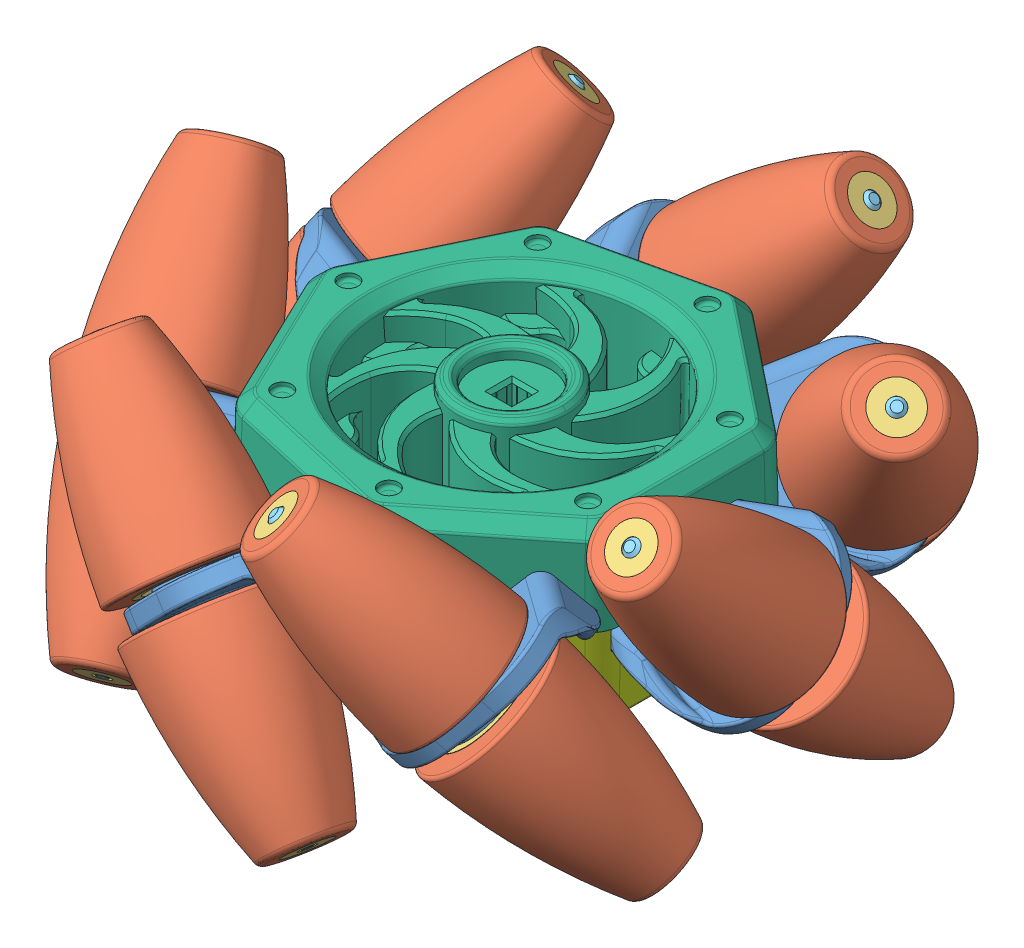
SolidWorks assembly Mecanum Right, configuration Default. Lengths in mm.
Overall size (110.3 64.91 110.26).
58 component instances, 7 part files, 0 mates.
Components (placement in the parent):
- Bracket Right-1: Bracket Right [Default] at (0 200 0) x (0.623334 0 -0.781956) z (-0.781956 0 -0.623334) size (28.34 25.51 28.03)
- Roller-2: Roller [Default] at (-36.4141 199.7525 -17.2503) x (0 -0.669407 -0.742896) z (0.951825 -0.227804 0.205269) size (22.31 28.6 22.31)
- Roller Hub-1: Roller Hub [Default] at (24.9941 200.1768 31.6042) x (0.175196 0.615989 -0.768026) z (-0.81476 -0.347214 -0.464337) size (15.2 28.65 15.2)
- Washer-3: Washer [Default] at (-15.7476 193.0527 -37.733) x (-0.491142 0.615989 0.615904) z (0.689343 0.707107 -0.157501) size (6 6 6.25)
- Washer-4: Washer [Default] at (-15.7278 206.9473 37.7412) x (0.709708 0.615989 -0.341865) z (-0.689425 0.707107 -0.15714) size (6 6 6.25)
- Roller-4: Roller [Default] at (40.2927 200.1768 0.1627) x (0 -0.707107 0.707107) z (1 -0.000175 -0.000175) size (22.31 28.6 22.31)
- Bracket Right-2: Bracket Right [Default] at (0 200 0) x (1 0 -0.000175) z (-0.000175 0 -1) size (28.34 25.51 28.03)
- Roller Hub-3: Roller Hub [Default] at (-36.2301 200.1768 -17.6326) x (0.17533 0.615989 0.767995) z (0.935537 -0.347214 0.064912) size (15.2 28.65 15.2)
- Roller Hub-4: Roller Hub [Default] at (25.3257 199.7525 31.3396) x (-0.175196 -0.615989 0.768026) z (-0.81476 -0.347214 -0.464337) size (15.2 28.65 15.2)
- Washer-7: Washer [Default] at (-2.202 206.9473 -40.8279) x (-0.491142 0.615989 0.615904) z (0.689343 0.707107 -0.157501) size (6 6 6.25)
- Roller-7: Roller [Default] at (-36.3744 200.1768 17.333) x (0 0.669314 0.74298) z (0.951717 0.228078 -0.205464) size (22.31 28.6 22.31)
- Roller-8: Roller [Default] at (40.2926 199.7525 -0.2616) x (0 0.707107 -0.707107) z (1 -0.000175 -0.000175) size (22.31 28.6 22.31)
- Bracket Right-3: Bracket Right [Default] at (0 200 0) x (0.623607 0 0.781738) z (0.781738 0 -0.623607) size (28.34 25.51 28.03)
- Roller Hub-5: Roller Hub [Default] at (-36.4141 199.7525 -17.2503) x (-0.17533 -0.615989 -0.767995) z (0.935537 -0.347214 0.064912) size (15.2 28.65 15.2)
- Washer-9: Washer [Default] at (30.5625 193.0527 27.1606) x (0.175196 0.615989 -0.768026) z (-0.552695 0.707107 0.441053) size (6 6 6.25)
- Pin-3: Pin [Default] at (25.0549 200.1061 31.5557) x (0.552772 0.707107 -0.440957) z (0.623743 -0.000175 0.781629) size (2.6 61.8 2.6)
- Roller-11: Roller [Default] at (25.254 200.1768 -31.3969) x (-0.787755 0.615989 0) z (-0.271506 -0.347214 0.897623) size (22.31 28.6 22.31)
- Roller-12: Roller [Default] at (-36.1902 199.7525 17.7152) x (0 -0.669314 -0.74298) z (0.951717 0.228078 -0.205464) size (22.31 28.6 22.31)
- Roller Hub-7: Roller Hub [Default] at (40.2927 200.1768 0.1627) x (-0.491249 0.615989 -0.615818) z (-0.871019 -0.347214 0.347518) size (15.2 28.65 15.2)
- Bracket Right-4: Bracket Right [Default] at (0 200 0) x (-0.222399 0 0.974956) z (0.974956 0 0.222399) size (28.34 25.51 28.03)
- Washer-12: Washer [Default] at (-39.3196 193.0527 -11.2132) x (0.17533 0.615989 0.767995) z (0.306643 0.707107 -0.637158) size (6 6 6.25)
- Washer-13: Washer [Default] at (19.7021 206.9473 35.8273) x (0.175196 0.615989 -0.768026) z (-0.552695 0.707107 0.441053) size (6 6 6.25)
- Pin-4: Pin [Default] at (-9.0508 200.1061 39.2631) x (0.689398 0.707107 0.15726) z (-0.222229 -0.000175 0.974994) size (2.6 61.8 2.6)
- Roller-15: Roller [Default] at (24.9223 199.7525 -31.6614) x (0.787755 -0.615989 0) z (-0.271506 -0.347214 0.897623) size (22.31 28.6 22.31)
- Roller Hub-9: Roller Hub [Default] at (-36.3744 200.1768 17.333) x (0.709768 0.615989 0.341741) z (0.634031 -0.347214 -0.690976) size (15.2 28.65 15.2)
- Roller Hub-10: Roller Hub [Default] at (40.2926 199.7525 -0.2616) x (0.491249 -0.615989 0.615818) z (-0.871019 -0.347214 0.347518) size (15.2 28.65 15.2)
- Bracket Right-5: Bracket Right [Default] at (0 200 0) x (-0.901001 0 -0.433816) z (-0.433816 0 0.901001) size (28.34 25.51 28.03)
- Washer-16: Washer [Default] at (-33.294 206.9473 -23.7334) x (0.17533 0.615989 0.767995) z (0.306643 0.707107 -0.637158) size (6 6 6.25)
- Roller-16: Roller [Default] at (-9.1266 200.1768 39.2459) x (-0.716002 -0.698098 0) z (-0.109699 0.112512 0.987576) size (22.31 28.6 22.31)
- Pin-6: Pin [Default] at (-36.3407 200.1061 17.4031) x (0.306866 0.707107 0.637051) z (-0.90085 -0.000175 0.434131) size (2.6 61.8 2.6)
- Roller Hub-15: Roller Hub [Default] at (25.254 200.1768 -31.3969) x (-0.787755 0.615989 0) z (-0.271506 -0.347214 0.897623) size (15.2 28.65 15.2)
- Roller Hub-16: Roller Hub [Default] at (-36.1902 199.7525 17.7152) x (-0.709768 -0.615989 -0.341741) z (0.634031 -0.347214 -0.690976) size (15.2 28.65 15.2)
- Washer-18: Washer [Default] at (40.2903 193.0527 -6.9614) x (-0.491249 0.615989 -0.615818) z (0.000247 0.707107 0.707107) size (6 6 6.25)
- Bracket Right-6: Bracket Right [Default] at (0 200 0) x (-0.22257 0 -0.974917) z (-0.974917 0 0.22257) size (28.34 25.51 28.03)
- Roller-18: Roller [Default] at (-8.8024 200.1768 -39.3198) x (-0.716044 0.698055 0) z (0.109944 0.112777 0.987519) size (22.31 28.6 22.31)
- Roller-19: Roller [Default] at (-8.7129 199.7525 39.3401) x (0.716002 0.698098 0) z (-0.109699 0.112512 0.987576) size (22.31 28.6 22.31)
- Pin-8: Pin [Default] at (-36.2639 200.1061 -17.5625) x (-0.306754 0.707107 0.637104) z (-0.901077 -0.000175 -0.433659) size (2.6 61.8 2.6)
- Roller Hub-19: Roller Hub [Default] at (24.9223 199.7525 -31.6614) x (0.787755 -0.615989 0) z (-0.271506 -0.347214 0.897623) size (15.2 28.65 15.2)
- Washer-21: Washer [Default] at (-33.2816 193.0527 23.7508) x (0.709768 0.615989 0.341741) z (-0.306977 0.707107 -0.636997) size (6 6 6.25)
- Washer-22: Washer [Default] at (40.2951 206.9473 6.9333) x (-0.491249 0.615989 -0.615818) z (0.000247 0.707107 0.707107) size (6 6 6.25)
- Bracket Right-7: Bracket Right [Default] at (0 200 0) x (-0.900926 0 0.433974) z (0.433974 0 0.900926) size (28.34 25.51 28.03)
- Roller-21: Roller [Default] at (-9.216 199.7525 -39.2253) x (0.716044 -0.698055 0) z (0.109944 0.112777 0.987519) size (22.31 28.6 22.31)
- Roller Hub-20: Roller Hub [Default] at (-9.1266 200.1768 39.2459) x (0.709708 0.615989 -0.341865) z (-0.144938 -0.347214 -0.926518) size (15.2 28.65 15.2)
- Pin-10: Pin [Default] at (-8.8782 200.1061 -39.3025) x (-0.68937 0.707107 0.15738) z (-0.22274 -0.000175 -0.974878) size (2.6 61.8 2.6)
- Washer-24: Washer [Default] at (19.6833 193.0527 -35.8376) x (-0.787755 0.615989 0) z (0.552926 0.707107 0.440764) size (6 6 6.25)
- Washer-25: Washer [Default] at (-39.3137 206.9473 11.2338) x (0.709768 0.615989 0.341741) z (-0.306977 0.707107 -0.636997) size (6 6 6.25)
- Roller-23: Roller [Default] at (24.9941 200.1768 31.6042) x (-0.787879 -0.61583 0) z (0.271614 -0.347497 0.897481) size (22.31 28.6 22.31)
- Hub Outer Right-1: Hub Outer Right [Default] at (0 200 0) x (1 0 0) z (0 0 -1) size (60.84 23.71 60.59)
- Roller Hub-25: Roller Hub [Default] at (-8.8024 200.1768 -39.3198) x (-0.491142 0.615989 0.615904) z (0.532528 -0.347214 0.771917) size (15.2 28.65 15.2)
- Roller Hub-26: Roller Hub [Default] at (-8.7129 199.7525 39.3401) x (-0.709708 -0.615989 0.341865) z (-0.144938 -0.347214 -0.926518) size (15.2 28.65 15.2)
- Pin-12: Pin [Default] at (25.1932 200.1061 -31.4454) x (-0.552849 0.707107 -0.44086) z (0.623334 -0.000175 -0.781956) size (2.6 61.8 2.6)
- Washer-27: Washer [Default] at (30.5483 206.9473 -27.1766) x (-0.787755 0.615989 0) z (0.552926 0.707107 0.440764) size (6 6 6.25)
- Roller-26: Roller [Default] at (-36.2301 200.1768 -17.6326) x (0 0.669407 0.742896) z (0.951825 -0.227804 0.205269) size (22.31 28.6 22.31)
- Roller-27: Roller [Default] at (25.3257 199.7525 31.3396) x (0.787879 0.61583 0) z (0.271614 -0.347497 0.897481) size (22.31 28.6 22.31)
- Hub Inner Right-1: Hub Inner Right [Default] at (0 200 0) x (1 0 0) z (0 0 -1) size (60.81 19.81 60.6)
- Roller Hub-28: Roller Hub [Default] at (-9.216 199.7525 -39.2253) x (0.491142 -0.615989 -0.615904) z (0.532528 -0.347214 0.771917) size (15.2 28.65 15.2)
- Washer-28: Washer [Default] at (-2.1806 193.0527 40.829) x (0.709708 0.615989 -0.341865) z (-0.689425 0.707107 -0.15714) size (6 6 6.25)
- Pin-14: Pin [Default] at (40.2927 200.1061 0.092) x (0 0.707107 -0.707107) z (1 -0.000175 -0.000175) size (2.6 61.8 2.6)
